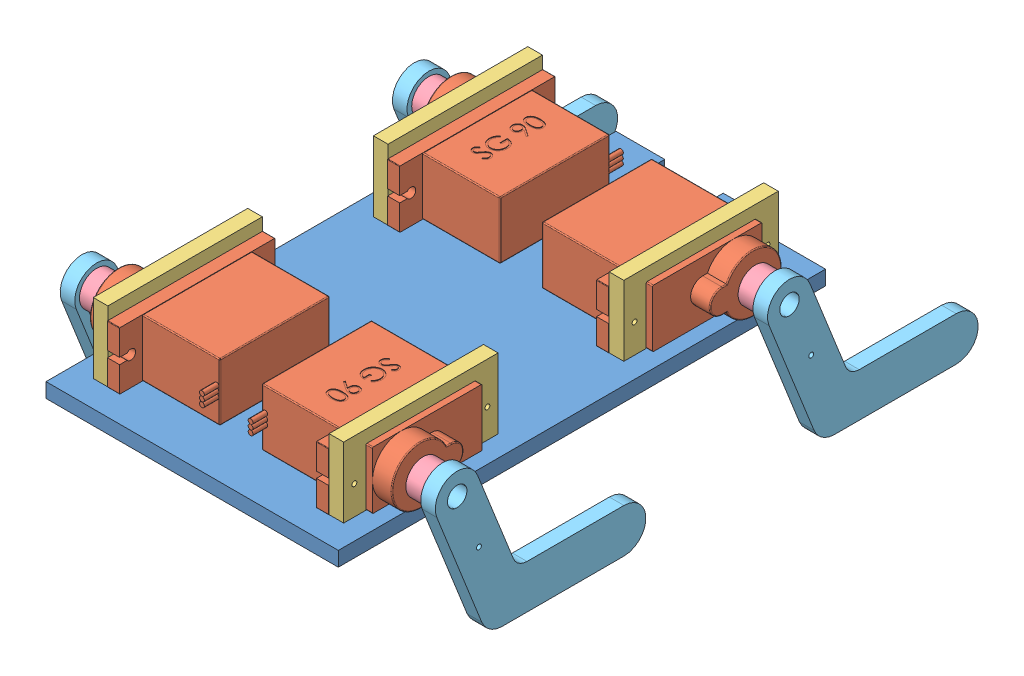
SolidWorks assembly mia, configuration Default. Lengths in mm.
Overall size (77 49.6 124.58).
17 component instances, 5 part files, 44 mates.
Components (placement in the parent):
- Base-1: Base [Default] at (-3.0224 29.2064 91.2375) size (60 3 103)
- sg90-1: sg90 [Default] at (22.6776 44.0064 1.2375) x (0 0 1) z (0 -1 0) size (31.9 29.9 11.8)
- sg90-2: sg90 [Default] at (31.2776 44.0064 81.2375) x (0 0 -1) z (0 -1 0) size (31.9 29.9 11.8)
- sg90-3: sg90 [Default] at (22.6776 32.2064 81.2375) x (0 0 -1) z (0 1 0) size (31.9 29.9 11.8)
- sg90-4: sg90 [Default] at (31.2776 32.2064 1.2375) x (0 0 1) z (0 1 0) size (31.9 29.9 11.8)
- servo_support-1: servo_support [Default] at (52.6776 29.2064 54.1375) x (0 0 1) z (-1 0 0) size (31.7 17.4 3)
- servo_support-2: servo_support [Default] at (52.6776 29.2064 -3.3625) x (0 0 1) z (-1 0 0) size (31.7 17.4 3)
- servo_support-3: servo_support [Default] at (4.2776 29.2064 -3.3625) x (0 0 1) z (-1 0 0) size (31.7 17.4 3)
- servo_support-4: servo_support [Default] at (4.2776 29.2064 54.1375) x (0 0 1) z (-1 0 0) size (31.7 17.4 3)
- SG90 plastic Horn-1: SG90 plastic Horn [Default] at (-6.5224 38.1064 7.1375) x (0 -0.929309 -0.369302) z (0 0.369302 -0.929309) size (23.76 4 7.07)
- SG90 plastic Horn-2: SG90 plastic Horn [Default] at (-6.5224 38.1064 75.3375) x (0 -0.929309 -0.369302) z (0 0.369302 -0.929309) size (23.76 4 7.07)
- SG90 plastic Horn-3: SG90 plastic Horn [Default] at (60.4776 38.1064 7.1375) x (0 -0.929309 -0.369302) z (0 -0.369302 0.929309) size (23.76 4 7.07)
- SG90 plastic Horn-4: SG90 plastic Horn [Default] at (60.4776 38.1064 75.3375) x (0 -0.929309 -0.369302) z (0 -0.369302 0.929309) size (23.76 4 7.07)
- leg-1: leg [Default] at (-8.5224 30.0148 -13.8515) x (0 -0.827436 0.561559) z (0 -0.561559 -0.827436) size (23.04 3 50.37)
- leg-2: leg [Default] at (-8.5224 30.0148 54.3485) x (0 -0.827436 0.561559) z (0 -0.561559 -0.827436) size (23.04 3 50.37)
- leg-3: leg [Default] at (65.4776 30.0148 -13.8515) x (0 -0.827436 0.561559) z (0 -0.561559 -0.827436) size (23.04 3 50.37)
- leg-4: leg [Default] at (65.4776 30.0148 54.3485) x (0 -0.827436 0.561559) z (0 -0.561559 -0.827436) size (23.04 3 50.37)
Mates (geometry in assembly coordinates):
- Coincident1: coincident: plane of Base-1 through (-3.0224 32.2064 91.2375) normal (0 1 0); plane of sg90-1 through (22.6776 32.2064 1.2375) normal (0 -1 0)
- Distance1: distance = 3 mm: plane of sg90-1 through (-0.0224 32.2064 1.2375) normal (-1 0 0); plane of Base-1 through (-3.0224 32.2064 91.2375) normal (-1 0 0)
- Distance3: distance = 10 mm: plane of sg90-1 through (22.6776 32.2064 1.2375) normal (0 0 -1); plane of Base-1 through (-3.0224 32.2064 -8.7625) normal (0 0 -1)
- Coincident5: coincident: plane of Base-1 through (-3.0224 32.2064 91.2375) normal (0 1 0); plane of sg90-2 through (31.2776 32.2064 81.2375) normal (0 -1 0)
- Coincident7: coincident: plane of Base-1 through (49.6776 32.2064 58.7375) normal (0 0 -1); plane of sg90-2 through (31.2776 32.2064 58.7375) normal (0 0 -1)
- Coincident8: coincident: plane of Base-1 through (49.6776 32.2064 81.2375) normal (1 0 0); plane of sg90-2 through (49.6776 44.0064 85.9375) normal (1 0 0)
- Coincident9: coincident: plane of Base-1 through (-3.0224 32.2064 91.2375) normal (0 1 0); plane of sg90-3 through (22.6776 32.2064 81.2375) normal (0 -1 0)
- Coincident10: coincident: plane of sg90-1 through (-0.0224 32.2064 1.2375) normal (-1 0 0); plane of sg90-3 through (-0.0224 44.0064 81.2375) normal (-1 0 0)
- Coincident11: coincident: plane of Base-1 through (4.2776 32.2064 81.2375) normal (0 0 1); plane of sg90-3 through (22.6776 44.0064 81.2375) normal (0 0 1)
- Coincident12: coincident: plane of Base-1 through (-3.0224 32.2064 91.2375) normal (0 1 0); plane of sg90-4 through (31.2776 32.2064 1.2375) normal (0 -1 0)
- Coincident13: coincident: plane of sg90-2 through (53.9776 32.2064 81.2375) normal (1 0 0); plane of sg90-4 through (53.9776 44.0064 1.2375) normal (1 0 0)
- Coincident14: coincident: plane of Base-1 through (49.6776 32.2064 1.2375) normal (0 0 -1); plane of sg90-4 through (31.2776 44.0064 1.2375) normal (0 0 -1)
- Coincident15: coincident: plane of Base-1 through (49.6776 32.2064 81.2375) normal (1 0 0); plane of servo_support-1 through (49.6776 29.2064 54.1375) normal (-1 0 0)
- Coincident16: coincident: plane of Base-1 through (49.6776 32.2064 85.8375) normal (0 0 -1); plane of servo_support-1 through (49.6776 29.2064 85.8375) normal (0 0 1)
- Coincident17: coincident: plane of Base-1 through (-3.0224 29.2064 91.2375) normal (0 -1 0); plane of servo_support-1 through (49.6776 29.2064 81.2375) normal (0 -1 0)
- Coincident18: coincident: plane of Base-1 through (49.6776 32.2064 23.7375) normal (1 0 0); plane of servo_support-2 through (49.6776 29.2064 -3.3625) normal (-1 0 0)
- Coincident20: coincident: plane of Base-1 through (49.6776 32.2064 23.7375) normal (0 0 1); plane of servo_support-2 through (49.6776 43.6064 23.7375) normal (0 0 -1)
- Coincident21: coincident: plane of Base-1 through (-3.0224 29.2064 91.2375) normal (0 -1 0); plane of servo_support-2 through (49.6776 29.2064 23.7375) normal (0 -1 0)
- Coincident22: coincident: plane of Base-1 through (4.2776 32.2064 1.2375) normal (-1 0 0); plane of servo_support-3 through (4.2776 29.2064 -3.3625) normal (1 0 0)
- Coincident23: coincident: plane of Base-1 through (4.2776 32.2064 -3.3625) normal (0 0 1); plane of servo_support-3 through (1.2776 46.6064 -3.3625) normal (0 0 -1)
- Coincident24: coincident: plane of Base-1 through (-3.0224 29.2064 91.2375) normal (0 -1 0); plane of servo_support-3 through (1.2776 29.2064 -3.3625) normal (0 -1 0)
- Coincident25: coincident: plane of Base-1 through (4.2776 32.2064 58.7375) normal (-1 0 0); plane of servo_support-4 through (4.2776 29.2064 54.1375) normal (1 0 0)
- Coincident26: coincident: plane of Base-1 through (-3.0224 29.2064 91.2375) normal (0 -1 0); plane of servo_support-4 through (1.2776 29.2064 54.1375) normal (0 -1 0)
- Coincident27: coincident: plane of Base-1 through (4.2776 32.2064 54.1375) normal (0 0 1); plane of servo_support-4 through (1.2776 46.6064 54.1375) normal (0 0 -1)
- Concentric1: concentric: circle of sg90-1; circle of SG90 plastic Horn-1
- Distance4: distance = 0.5 mm: plane of SG90 plastic Horn-1 through (-4.5224 35.8993 6.2604) normal (1 0 0); plane of sg90-1 through (-4.0224 38.1064 7.1375) normal (-1 0 0)
- Concentric2: concentric: circle of sg90-3; circle of SG90 plastic Horn-2
- Distance5: distance = 0.5 mm: plane of SG90 plastic Horn-2 through (-4.5224 35.8993 74.4604) normal (1 0 0); plane of sg90-3 through (-4.0224 38.1064 75.3375) normal (-1 0 0)
- Concentric3: concentric: circle of sg90-4; circle of SG90 plastic Horn-3
- Distance6: distance = 0.5 mm: plane of sg90-4 through (57.9776 38.1064 7.1375) normal (1 0 0); plane of SG90 plastic Horn-3 through (58.4776 35.8993 6.2604) normal (-1 0 0)
- Concentric4: concentric: circle of sg90-2; circle of SG90 plastic Horn-4
- Distance7: distance = 0.5 mm: plane of SG90 plastic Horn-4 through (58.4776 35.8993 74.4604) normal (-1 0 0); plane of sg90-2 through (57.9776 38.1064 75.3375) normal (1 0 0)
- Concentric5: concentric: circle of SG90 plastic Horn-1; circle of leg-1
- Coincident32: coincident: plane of SG90 plastic Horn-1 through (-8.5224 34.8213 5.8321) normal (-1 0 0); plane of leg-1 through (-8.5224 38.1064 7.1375) normal (1 0 0)
- Concentric7: concentric: circle of SG90 plastic Horn-1; circle of leg-1
- Concentric8: concentric: circle of SG90 plastic Horn-2; circle of leg-2
- Coincident35: coincident: plane of SG90 plastic Horn-2 through (-8.5224 34.8213 74.0321) normal (-1 0 0); plane of leg-2 through (-8.5224 38.1064 75.3375) normal (1 0 0)
- Concentric9: concentric: circle of SG90 plastic Horn-2; circle of leg-2
- Concentric10: concentric: circle of SG90 plastic Horn-3; circle of leg-3
- Coincident37: coincident: plane of SG90 plastic Horn-3 through (62.4776 34.8213 5.8321) normal (1 0 0); plane of leg-3 through (62.4776 38.1064 7.1375) normal (-1 0 0)
- Concentric11: concentric: circle of SG90 plastic Horn-3; circle of leg-3
- Concentric12: concentric: circle of SG90 plastic Horn-4; circle of leg-4
- Coincident39: coincident: plane of SG90 plastic Horn-4 through (62.4776 34.8213 74.0321) normal (1 0 0); plane of leg-4 through (62.4776 38.1064 75.3375) normal (-1 0 0)
- Concentric13: concentric: circle of SG90 plastic Horn-4; circle of leg-4
